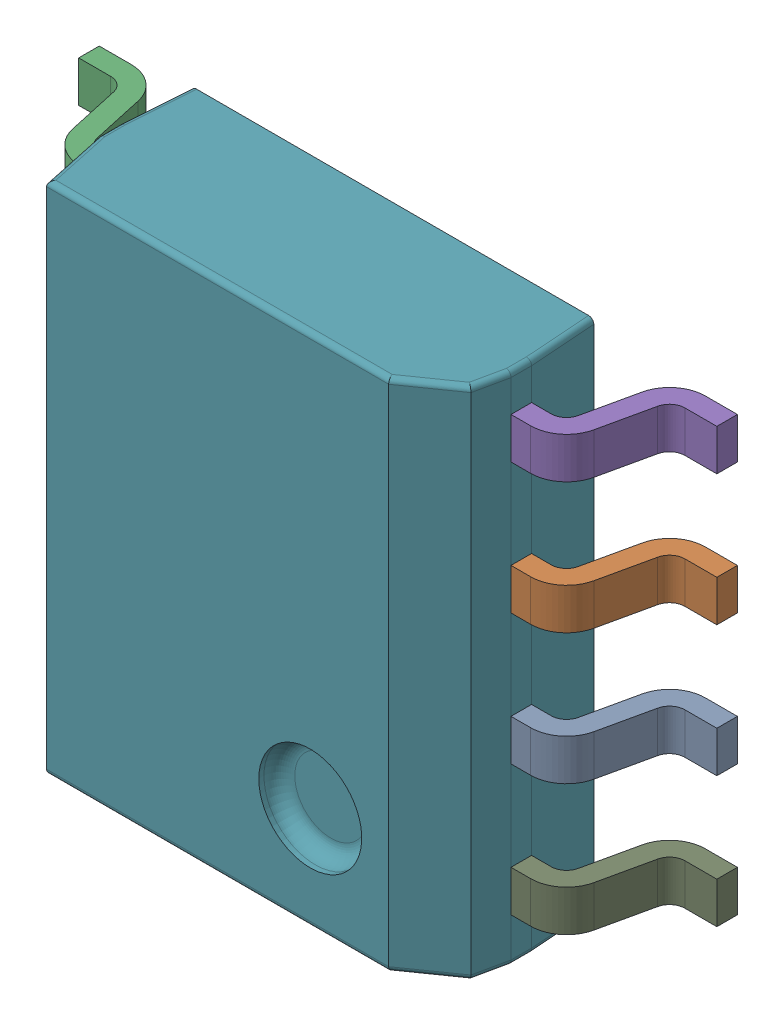
SolidWorks assembly U2, configuration Default. Lengths in mm.
Overall size (6.2 5 1.75).
10 component instances, 2 part files, 0 mates.
Components (placement in the parent):
- User_Library-SOIC-8-150_1-1: User_Library-SOIC-8-150_1 [Default] at (6.9849 6.3501 1) x (0 -1 0) z (-1 0 0) size (5 1.75 6.2)
  - User_Library-SOIC-8-150_pin_SOIC_SO-150_1-1: User_Library-SOIC-8-150_pin_SOIC_SO-150_1 [Default] at (0.6 0 -2) x (-1 0 0) z (0 0 -1) size (0.4 1.1 1.1)
  - User_Library-SOIC-8-150_pin_SOIC_SO-150_1-2: User_Library-SOIC-8-150_pin_SOIC_SO-150_1 [Default] at (-0.67 0 -2) x (-1 0 0) z (0 0 -1) size (0.4 1.1 1.1)
  - User_Library-SOIC-8-150_pin_SOIC_SO-150_1-3: User_Library-SOIC-8-150_pin_SOIC_SO-150_1 [Default] at (-1.94 0 2) size (0.4 1.1 1.1)
  - User_Library-SOIC-8-150_pin_SOIC_SO-150_1-4: User_Library-SOIC-8-150_pin_SOIC_SO-150_1 [Default] at (-0.67 0 2) size (0.4 1.1 1.1)
  - User_Library-SOIC-8-150_pin_SOIC_SO-150_1-5: User_Library-SOIC-8-150_pin_SOIC_SO-150_1 [Default] at (-1.94 0 -2) x (-1 0 0) z (0 0 -1) size (0.4 1.1 1.1)
  - User_Library-SOIC-8-150_pin_SOIC_SO-150_1-6: User_Library-SOIC-8-150_pin_SOIC_SO-150_1 [Default] at (1.87 0 2) size (0.4 1.1 1.1)
  - User_Library-SOIC-8-150_SOIC_150_SOIC_5X4_1-1: User_Library-SOIC-8-150_SOIC_150_SOIC_5X4_1 [Default] at origin size (5 1.5 4)
  - User_Library-SOIC-8-150_pin_SOIC_SO-150_1-7: User_Library-SOIC-8-150_pin_SOIC_SO-150_1 [Default] at (0.6 0 2) size (0.4 1.1 1.1)
  - User_Library-SOIC-8-150_pin_SOIC_SO-150_1-8: User_Library-SOIC-8-150_pin_SOIC_SO-150_1 [Default] at (1.87 0 -2) x (-1 0 0) z (0 0 -1) size (0.4 1.1 1.1)
